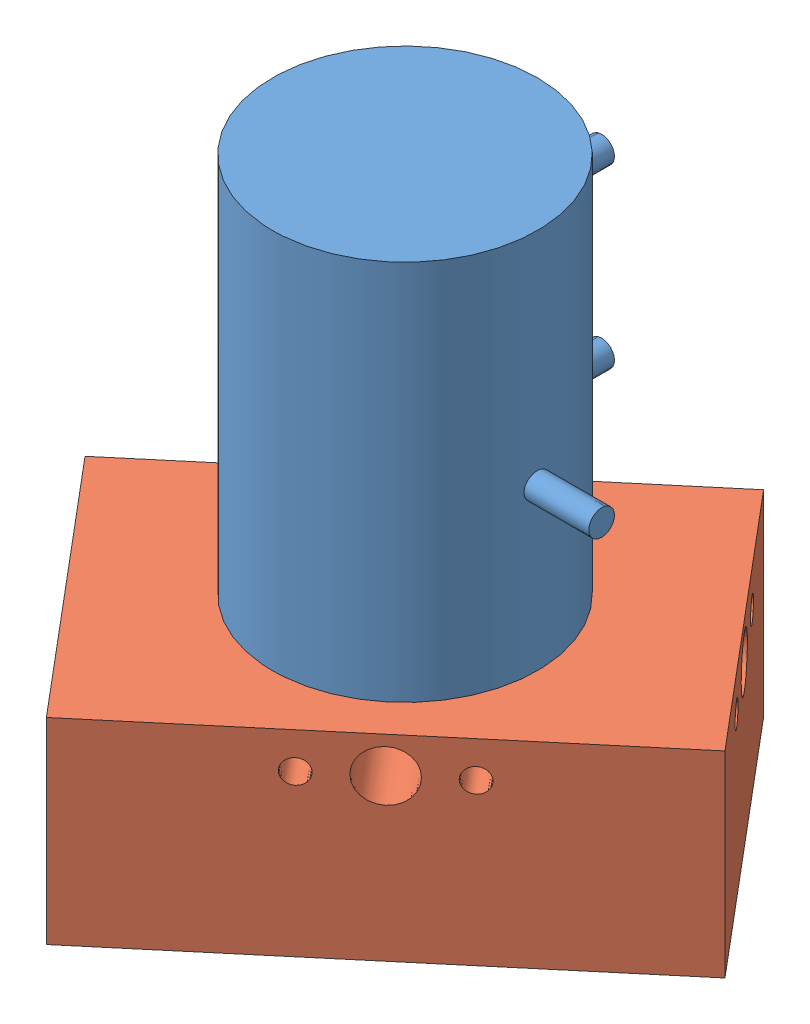
SolidWorks assembly Assem1, configuration Default. Lengths in mm.
Overall size (71.66 78 69.25).
2 component instances, 2 part files, 2 mates.
Components (placement in the parent):
- DAVIS346_lens-1: DAVIS346_lens [Default] at (-105.1233 -22.2896 57.728) size (41 51.5 41)
- DAVIS346-1: DAVIS346 [Default] at (-69.2944 -23.2896 53.692) x (-0.76473 0 0.644351) z (0 -1 0) size (60 40 30.5)
Mates (geometry in assembly coordinates):
- Coincident1: coincident: cylinder of DAVIS346_lens-1 through (-105.1233 -26.2896 57.728) axis (0 1 0) radius 14; circle of DAVIS346-1
- Coincident2: coincident anti-aligned: plane of DAVIS346_lens-1 through (-105.1233 -22.2896 57.728) normal (0 -1 0); plane of DAVIS346-1 through (-105.1233 -22.2896 57.728) normal (0 1 0)
